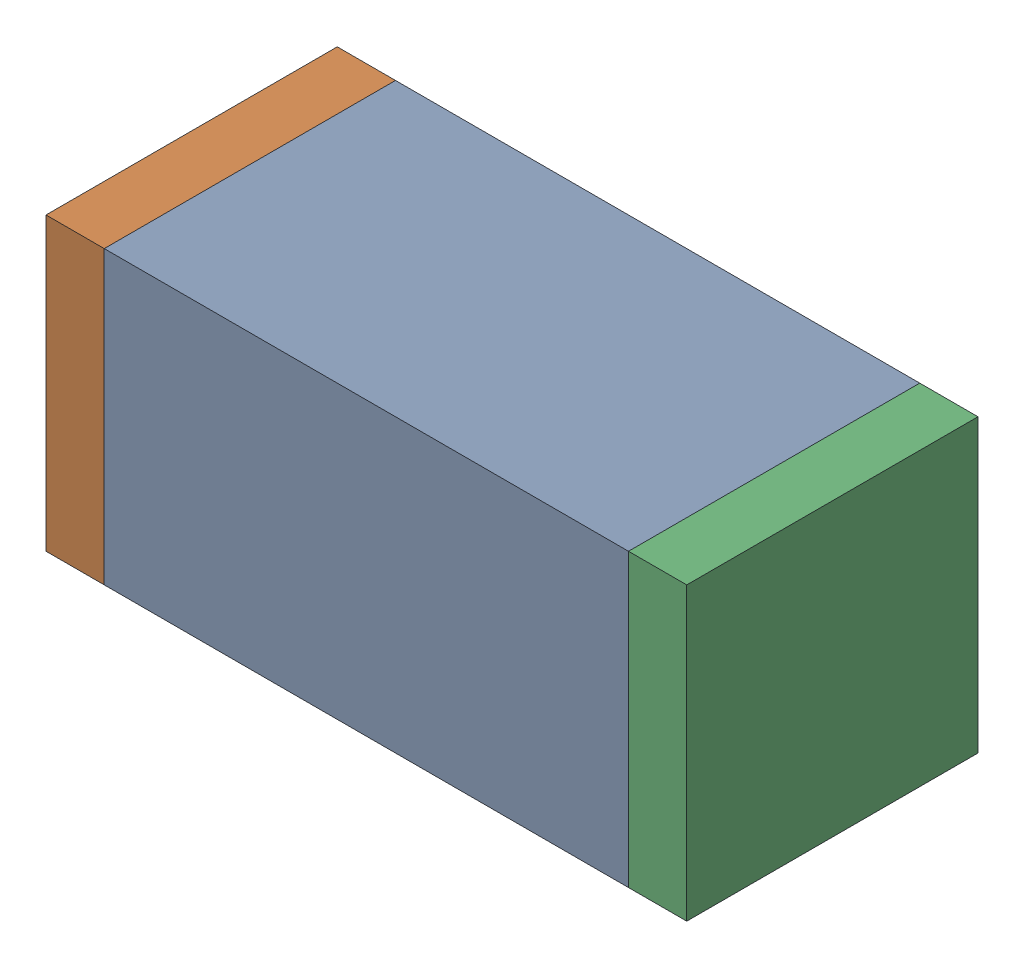
SolidWorks assembly C39, configuration Default. Lengths in mm.
Overall size (1.1 0.5 0.5).
6 component instances, 2 part files, 0 mates.
Components (placement in the parent):
- 836749680-1: 836749680 [Default] at (120.45 34.8 0) size (0.9 0.5 0.5)
  - Extruded_4-1: Extruded_4 [Default] at origin size (0.9 0.5 0.5)
- 810156080-1: 810156080 [Default] at (119.95 34.8 0) size (0.1 0.5 0.5)
  - Extruded_5-1: Extruded_5 [Default] at origin size (0.1 0.5 0.5)
- 810156080-2: 810156080 [Default] at (120.95 34.8 0) size (0.1 0.5 0.5)
  - Extruded_5-1: Extruded_5 [Default] at origin size (0.1 0.5 0.5)
